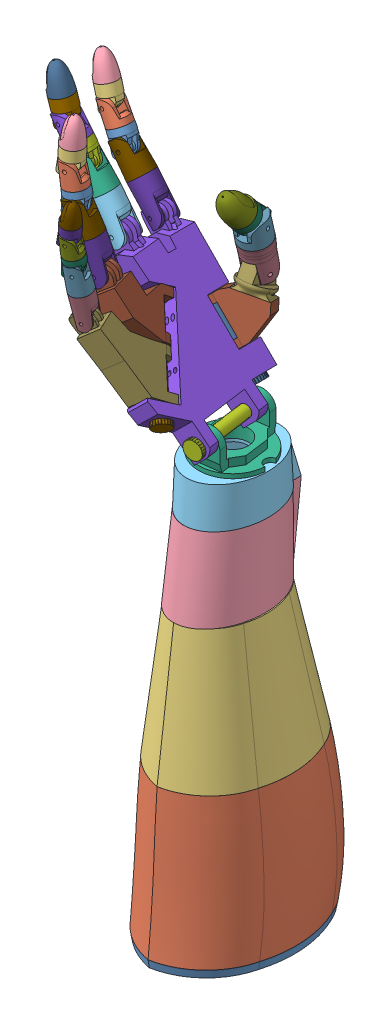
SolidWorks assembly brat bionic, configuration Default. Lengths in mm.
Overall size (186.55 465.52 156.46).
47 component instances, 36 part files, 51 mates.
Components (placement in the parent):
- capac-1: capac [Default] x (0 0 1) z (0 -1 0) size (118 85.51 15.8)
- brat-1: brat [Default] at (21.3792 100.51 -54.6588) x (0 0 1) z (0 1 0) size (122.64 91.01 100.55)
- brat3-1: brat3 [Default] at (23.3637 100.51 -0.673) x (0 0 1) z (0 1 0) size (108.18 78.67 92.99)
- rotatie3-1: rotatie3 [Default] at (21.3637 247.6 0.827) x (0 -1 0) z (0 0 -1) size (54.52 53.72 79.07)
- rotatie2-1: rotatie2 [Default] at (21.3637 275.1 2.3667) x (0 0 1) z (0 1 0) size (71.08 50.43 27.52)
- rotatie-1: rotatie [Default] at (21.3637 275.1 0.7767) x (0 1 0) z (-0.134965 0 -0.99085) size (25.5 46.57 47)
- kama3-1: kama3 [Default] at (18.3095 293.6 -21.6462) x (0.134965 0 0.99085) z (0.641333 0.762273 -0.087357) size (55.22 12.11 12.06)
- incheietura-1: incheietura [Default] at (-20.546 325.2368 8.0367) x (0.134965 0 0.99085) z (0.711445 0.696028 -0.096907) size (89.87 119.48 17.05)
- kama1-1: kama1 [Default] at (-35.8574 351.6273 -2.537) x (0.618123 -0.554197 0.557484) z (-0.539894 -0.814768 -0.211345) size (81.63 11.99 11.99)
- kama2-1: kama2 [Default] at (-28.3654 340.8502 -24.9402) x (0.698485 -0.715535 -0.011329) z (-0.351682 -0.329428 -0.87624) size (58.94 11.99 11.99)
- deget 1-1: deget 1 [Default] at (-10.4486 326.1862 -38.0623) x (-0.698485 0.715535 0.011329) z (0.449436 0.426297 0.785034) size (30.12 34.69 17)
- deget mare-2: deget mare [Default] at (-3.1473 338.5582 -37.8147) x (-0.892295 0.172293 0.417283) z (0.04263 -0.888024 0.457817) size (43.45 64.19 58.55)
  - deget3-1: deget3 [Default] at origin size (24.28 22.96 17.51)
  - deget 2-1: deget 2 [Default] at (5.185 -11.6868 -28.9168) x (-0.905973 -0.423336 0) z (-0.262459 0.561682 0.78462) size (20 20 23)
  - deget-1: deget [Default] at (9.1429 -20.157 -40.7488) x (-0.262459 0.561682 0.78462) z (0.332158 -0.710844 0.619977) size (15.08 20.32 19.9)
  - Thump50-1: Thump50 [Default] at (12.6343 -27.6289 -42.1434) x (-0.167923 0.359369 -0.917963) z (-0.388607 0.831649 0.396666) size (19.12 18.1 18.16)
  - deget4-1: deget4 [Default] at (12.6343 -27.6289 -42.1434) x (0.905973 0.423336 0) z (-0.167923 0.359369 -0.917963) size (18 20.37 18.06)
- deget ia montaj-1: deget ia montaj [Default] at (-66.7389 383.6858 -24.7443) x (0.747821 0.656828 -0.096648) z (0.067683 0.069391 0.995291) size (32.62 95.22 17)
  - deget ia 3-4-1: deget ia 3-4 [Default] x (0 0 -1) z (-1 0 0) size (17 27 17)
  - deget ia 3-3-1: deget ia 3-3 [Default] x (0 -1 0) z (-1 0 0) size (22 17 17)
  - deget ia 3-5-1: deget ia 3-5 [Default] at (2.7147 27.1045 0) x (-0.225156 -0.974323 0) z (0 0 -1) size (17.26 16.52 15.41)
  - deget ia 3-6-1: deget ia 3-6 [Default] at (6.3172 42.6936 0) x (-0.225156 -0.974323 0) z (0.974323 -0.225156 0) size (16 15.32 14.93)
  - deget ia 3-2-1: deget ia 3-2 [Default] at (9.7593 49.8172 0) x (-0.920423 0.390924 0) z (-0.390924 -0.920423 0) size (14.75 14.1 18.07)
  - deget ia-1: deget ia [Default] at (9.7556 49.8188 0) x (0 0 1) z (-0.920423 0.390924 0) size (14.02 17.03 14.02)
- deget mijlociu-1: deget mijlociu [Default] at (-64.843 389.2399 3.6172) x (0.567542 -0.821624 -0.053198) z (-0.814812 -0.569765 0.107005) size (101.44 17.94 26.5)
  - major3-4-1: major3-4 [Default] x (0 -1 0) z (0 0 1) size (17.93 28.49 17.93)
  - major3-3-1: major3-3 [Default] at origin size (23.21 17.94 17.94)
  - major3-5-1: major3-5 [Default] at (-28.8122 0 -0.4421) x (0.999391 0 0.034899) z (0 -1 0) size (18.44 17.85 16.26)
  - major3-6-1: major3-6 [Default] at (-45.6819 0 -1.0313) x (0.999391 0 0.034899) z (0.034899 0 -0.999391) size (16.88 16.16 15.75)
  - major3-2-1: major3-2 [Default] at (-53.3574 0 -4.4512) x (-0.303003 0 0.952989) z (0.952989 0 0.303003) size (15.56 14.88 19.06)
  - articulatiemijlociu3-1: articulatiemijlociu3 [Default] at (-53.3587 0 -4.4471) x (0 1 0) z (-0.303003 0 0.952989) size (14.79 18.22 14.79)
- incheietura_-1: incheietura_ [Default] at (-23.9621 335.2236 29.2357) x (-0.301994 0.002725 -0.953306) z (0.758691 0.606179 -0.23861) size (37.9 57.51 17.01)
- incheietura2-1: incheietura2 [Default] at (-11.4977 349.8977 38.8133) x (0.21164 0.074147 0.974531) z (-0.75105 -0.625719 0.210714) size (41.78 67.66 17.05)
- articulatie3 montaj-1: articulatie3 montaj [Default] at (-26.8489 376.2709 57.3242) x (0.09602 -0.980205 -0.173144) z (-0.92614 -0.151721 0.345319) size (80.07 14.17 19.79)
  - articulatie3-4-1: articulatie3-4 [Default] x (0 -1 0) z (0 0 1) size (14.17 22.51 14.17)
  - articulatie3-3-1: articulatie3-3 [Default] at origin size (18.34 14.17 14.17)
  - articulatie3-5-1: articulatie3-5 [Default] at (-22.7616 0 -0.5946) x (0.998236 0 0.05937) z (0 -1 0) size (14.57 13.77 12.85)
  - articulatie3-6-1: articulatie3-6 [Default] at (-36.0741 0 -1.3863) x (0.998236 0 0.05937) z (0.05937 0 -0.998236) size (13.34 12.77 12.44)
  - articulatie3-2-2: articulatie3-2 [Default] at (-42.4072 0 -3.224) x (-0.23181 0 0.972761) z (0.972761 0 0.23181) size (12.3 11.75 15.1)
  - articulatie3-1: articulatie3 [Default] at (-42.408 0 -3.2207) x (0 1 0) z (-0.23181 0 0.972761) size (11.69 14.19 11.69)
- deget ia montaj-2: deget ia montaj [Default] at (-45.356 388.3921 33.2055) x (0.885704 0.376168 -0.272078) z (0.286321 0.018719 0.957951) size (32.62 95.22 17)
  - deget ia 3-4-1: deget ia 3-4 [Default] x (0 0 -1) z (-1 0 0) size (17 27 17)
  - deget ia 3-3-1: deget ia 3-3 [Default] x (0 -1 0) z (-1 0 0) size (22 17 17)
  - deget ia 3-5-1: deget ia 3-5 [Default] at (2.7147 27.1045 0) x (-0.225156 -0.974323 0) z (0 0 -1) size (17.26 16.52 15.41)
  - deget ia 3-6-1: deget ia 3-6 [Default] at (6.3172 42.6936 0) x (-0.225156 -0.974323 0) z (0.974323 -0.225156 0) size (16 15.32 14.93)
  - deget ia 3-2-1: deget ia 3-2 [Default] at (9.7593 49.8172 0) x (-0.920423 0.390924 0) z (-0.390924 -0.920423 0) size (14.75 14.1 18.07)
  - deget ia-1: deget ia [Default] at (9.7556 49.8188 0) x (0 0 1) z (-0.920423 0.390924 0) size (14.02 17.03 14.02)
Mates (geometry in assembly coordinates):
- Coincident1: coincident anti-aligned: plane of capac-1 through (0 0 0) normal (0 -1 0)
- Coincident2: coincident anti-aligned: plane of capac-1 through (0 0 0) normal (-1 0 0)
- Coincident3: coincident aligned: plane of capac-1 through (0 0 0) normal (0 0 1)
- Concentric8: concentric aligned: circle of capac-1; circle of brat-1
- Coincident4: coincident anti-aligned: plane of capac-1 through (27.0674 0 -14.9828) normal (0 1 0); plane of brat-1 through (12.3179 0 10.0833) normal (0 -1 0)
- Parallel1: parallel aligned: plane of brat-1 through (21.3792 100.51 -54.6588) normal (1 0 0)
- Concentric10: concentric aligned: circle of brat-1; circle of brat3-1
- Coincident5: coincident anti-aligned: plane of brat-1 through (16.2073 100.51 -14.3784) normal (0 1 0); plane of brat3-1 through (15.3542 100.51 -13.3417) normal (0 -1 0)
- Parallel2: parallel aligned: plane of brat-1 through (21.3792 100.51 -54.6588) normal (1 0 0); plane of brat3-1 through (23.3637 100.51 -0.673) normal (1 0 0)
- Distance5: distance = 2 mm anti-aligned: plane of brat3-1 through (23.3637 100.51 -0.673) normal (1 0 0); plane of rotatie3-1 through (21.3637 247.6 0.827) normal (-1 0 0)
- Coincident7: coincident anti-aligned: plane of brat3-1 through (17.2122 193.1 -4.2925) normal (0 1 0); plane of rotatie3-1 through (21.3637 193.1 4.397) normal (0 -1 0)
- Distance6: distance = 1.5 mm anti-aligned: plane of rotatie3-1 through (21.3637 247.6 0.827) normal (0 0 -1); plane of brat3-1 through (23.3637 100.51 -0.673) normal (0 0 1)
- Coincident9: coincident anti-aligned: plane of rotatie3-1 through (21.3637 247.6 0.827) normal (0 1 0); plane of rotatie2-1 through (21.4437 247.6 0.7167) normal (0 -1 0)
- Coincident10: coincident anti-aligned: line of rotatie3-1 through (10.5337 247.6 -35.6949) axis (1 0 0); line of rotatie2-1 through (32.1137 247.6 -35.6949) axis (-1 0 0)
- Coincident12: coincident anti-aligned: plane of rotatie3-1 through (21.3637 247.6 0.827) normal (-1 0 0); plane of rotatie2-1 through (21.3637 275.1 2.3667) normal (1 0 0)
- Concentric11: concentric anti-aligned: cylinder of rotatie2-1; cylinder of rotatie-1 through (21.3637 278.1 0.7767) axis (0 -1 0) radius 10.75
- Coincident14: coincident anti-aligned: plane of rotatie2-1 through (21.3637 275.1 0.7767) normal (0 1 0); plane of rotatie-1 through (33.0062 275.1 -0.8091) normal (0 -1 0)
- Concentric12: concentric aligned: cylinder of rotatie-1 through (25.945 293.6 34.4099) axis (-0.134965 0 -0.99085) radius 4; cylinder of kama3-1 through (25.3466 293.6 30.0167) axis (-0.134965 0 -0.99085) radius 4
- Coincident15: coincident anti-aligned: circle of kama3-1; plane of rotatie-1 through (27.5591 300.6 -22.9061) normal (-0.134965 0 -0.99085)
- Concentric13: concentric aligned: cylinder of kama3-1 through (25.3466 293.6 30.0167) axis (-0.134965 0 -0.99085) radius 4; cylinder of incheietura-1 through (26.8735 293.6 41.2269) axis (-0.134965 0 -0.99085) radius 4
- Coincident16: coincident anti-aligned: plane of rotatie-1 through (33.6676 300.6 21.9398) normal (0.134965 0 0.99085); plane of incheietura-1 through (23.9886 306.2592 23.2582) normal (-0.134965 0 -0.99085)
- LimitAngle13: limit planar angle = 0.779243 rad aligned: plane of incheietura-1 through (-20.546 325.2368 8.0367) normal (0.711445 0.696028 -0.096907)
- Concentric14: concentric anti-aligned: cylinder of incheietura-1 through (-36.2983 352.0226 -2.9347) axis (0.618123 -0.554197 0.557484) radius 4; cylinder of kama1-1 through (12.7456 308.0507 41.298) axis (-0.618123 0.554197 -0.557484) radius 4
- Coincident17: coincident anti-aligned: plane of incheietura-1 through (22.898 308.3614 30.3503) normal (0.618123 -0.554197 0.557484); plane of kama1-1 through (12.7456 308.0507 41.298) normal (-0.618123 0.554197 -0.557484)
- Concentric15: concentric anti-aligned: cylinder of incheietura-1 through (-28.3233 340.807 -24.9409) axis (0.698485 -0.715535 -0.011329) radius 4; cylinder of kama2-1 through (10.7079 300.8231 -25.574) axis (-0.698485 0.715535 0.011329) radius 4
- Coincident18: coincident anti-aligned: plane of incheietura-1 through (16.091 306.2266 -34.9567) normal (0.698485 -0.715535 -0.011329); plane of kama2-1 through (10.7079 300.8231 -25.574) normal (-0.698485 0.715535 0.011329)
- Concentric16: concentric aligned: cylinder of kama2-1 through (10.7079 300.8231 -25.574) axis (-0.698485 0.715535 0.011329) radius 4; cylinder of deget 1-1 through (2.8199 308.9037 -25.4461) axis (-0.698485 0.715535 0.011329) radius 4
- Symmetric1: symmetric aligned: plane of deget 1-1 through (-13.0589 342.3726 -23.7025) normal (-0.698485 0.715535 0.011329); plane of deget 1-1 through (-0.3752 312.5207 -14.7534) normal (0.698485 -0.715535 -0.011329)
- Coincident20: coincident anti-aligned: plane of deget 1-1 through (10.8219 340.0938 -36.1369) normal (-0.04263 0.888024 -0.457817); plane of deget mare-2/deget3-1 through (-3.1473 338.5582 -37.8147) normal (0.04263 -0.888024 0.457817)
- Coincident21: coincident aligned: line of deget 1-1 through (10.8219 340.0938 -36.1369) axis (-0.892295 0.172293 0.417283); line of deget mare-2/deget3-1 through (10.8219 340.0938 -36.1369) axis (-0.892295 0.172293 0.417283)
- Coincident22: coincident anti-aligned: line of deget 1-1 through (10.8219 340.0938 -36.1369) axis (-0.449436 -0.426297 -0.785034); line of deget mare-2/deget3-1 through (3.1815 332.8467 -49.4825) axis (0.449436 0.426297 0.785034)
- Concentric17: concentric anti-aligned: cylinder of incheietura-1 through (-48.3241 373.3912 57.0965) axis (-0.067683 -0.069391 -0.995291) radius 1.25; cylinder of deget ia montaj-1/deget ia 3-4-1 through (-55.7007 365.8285 -51.3777) axis (0.067683 0.069391 0.995291) radius 1.25
- Coincident23: coincident anti-aligned: plane of incheietura-1 through (-51.9836 376.5313 -29.7702) normal (-0.067683 -0.069391 -0.995291); plane of deget ia montaj-1/deget ia 3-4-1 through (-60.6862 388.9572 -30.0447) normal (0.067683 0.069391 0.995291)
- Concentric18: concentric aligned: cylinder of incheietura-1 through (-52.7807 371.0116 7.2867) axis (0.118229 0.017384 0.992834) radius 1.25; cylinder of deget mijlociu-1/major3-4-1 through (-56.7103 370.4338 -25.7126) axis (0.118229 0.017384 0.992834) radius 1.3188
- Coincident24: coincident anti-aligned: plane of incheietura-1 through (-51.6759 380.0037 -2.5708) normal (-0.118229 -0.017384 -0.992834); plane of deget mijlociu-1/major3-4-1 through (-58.0966 394.2674 -2.056) normal (0.118229 0.017384 0.992834)
- Coincident25: coincident anti-aligned: plane of incheietura-1 through (-22.0638 349.6577 -3.1306) normal (0.618123 -0.554197 0.557484); plane of incheietura_-1 through (-26.4369 359.3113 11.3148) normal (-0.618123 0.554197 -0.557484)
- Concentric19: concentric aligned: cylinder of kama1-1 through (12.7456 308.0507 41.298) axis (-0.618123 0.554197 -0.557484) radius 4; cylinder of incheietura_-1 through (-4.1315 323.1825 26.0765) axis (-0.618123 0.554197 -0.557484) radius 4
- Concentric20: concentric anti-aligned: cylinder of kama1-1 through (12.7456 308.0507 41.298) axis (-0.618123 0.554197 -0.557484) radius 4; cylinder of incheietura2-1 through (-16.5183 334.2882 14.9048) axis (0.618123 -0.554197 0.557484) radius 4
- Coincident26: coincident anti-aligned: plane of incheietura-1 through (9.5333 324.4826 48.0226) normal (-0.618123 0.554197 -0.557484); plane of incheietura2-1 through (-1.433 314.5034 50.2614) normal (0.618123 -0.554197 0.557484)
- Concentric21: concentric aligned: cylinder of incheietura2-1 through (-28.2782 360.2367 48.6196) axis (0.364753 -0.127198 0.922375) radius 1.25; cylinder of articulatie3 montaj-1/articulatie3-4-1 through (-34.112 362.2711 33.8674) axis (0.364753 -0.127198 0.922375) radius 1.0419
- Coincident27: coincident anti-aligned: plane of incheietura2-1 through (-30.3658 349.4639 50.9518) normal (-0.364753 0.127198 -0.922375); plane of articulatie3 montaj-1/articulatie3-4-1 through (-19.4226 355.0369 47.3929) normal (0.364753 -0.127198 0.922375)
- Concentric22: concentric aligned: cylinder of incheietura_-1 through (-37.4022 369.1452 35.7975) axis (0.286321 0.018719 0.957951) radius 1.25; cylinder of deget ia montaj-2/deget ia 3-4-1 through (-46.3927 368.5574 5.7178) axis (0.286321 0.018719 0.957951) radius 1.25
- Coincident28: coincident anti-aligned: plane of incheietura_-1 through (-12.7328 345.4195 19.597) normal (-0.286321 -0.018719 -0.957951); plane of deget ia montaj-2/deget ia 3-4-1 through (-39.1151 391.5056 26.5818) normal (0.286321 0.018719 0.957951)
- LimitAngle3: limit planar angle = 0.174533 rad: plane of assembly through (156.1463 152.7624 -21.2689) normal (0.711445 0.696028 -0.096907); plane of assembly; plane of incheietura_-1 through (-23.9621 335.2236 29.2357) normal (0.758691 0.606179 -0.23861)
- LimitAngle5: limit planar angle = 0.576254 rad: plane of assembly through (1.3067 0 9.593) normal (0.134965 0 0.99085); plane of assembly; plane of deget 1-1 through (-10.4486 326.1862 -38.0623) normal (0.449436 0.426297 0.785034)
- Angle2: planar angle = 3.001966 rad anti-aligned: plane of incheietura2-1 through (-24.2656 339.2605 42.3954) normal (-0.75105 -0.625719 0.210714); plane of incheietura-1 through (-20.546 325.2368 8.0367) normal (-0.711445 -0.696028 0.096907)
- LimitAngle6: limit planar angle = 0.053484 rad anti-aligned: plane of deget ia montaj-1/deget ia 3-4-1 through (-66.7389 383.6858 -24.7443) normal (-0.747821 -0.656828 0.096648); plane of incheietura-1 through (-8.4515 337.0692 6.3893) normal (0.711445 0.696028 -0.096907)
- LimitAngle7: limit planar angle = 0.163672 rad anti-aligned: plane of deget mijlociu-1 through (-64.843 389.2399 3.6172) normal (-0.814812 -0.569765 0.107005); plane of incheietura-1 through (-8.4515 337.0692 6.3893) normal (0.711445 0.696028 -0.096907)
- LimitAngle10: limit planar angle = 3.006214 rad anti-aligned: plane of rotatie-1 through (21.3637 275.1 0.7767) normal (0.99085 0 -0.134965); plane of rotatie2-1 through (21.3637 275.1 2.3667) normal (1 0 0)
- LimitAngle14: limit planar angle = 0.265654 rad aligned: plane of deget ia montaj-2 through (-45.356 388.3921 33.2055) normal (0.885704 0.376168 -0.272078); plane of incheietura_-1 through (-11.0643 345.5286 25.1793) normal (0.758691 0.606179 -0.23861)
- LimitAngle15: limit planar angle = 0.529073 rad anti-aligned: plane of articulatie3 montaj-1 through (-26.8489 376.2709 57.3242) normal (-0.92614 -0.151721 0.345319); plane of incheietura2-1 through (-11.4977 349.8977 38.8133) normal (0.75105 0.625719 -0.210714)
